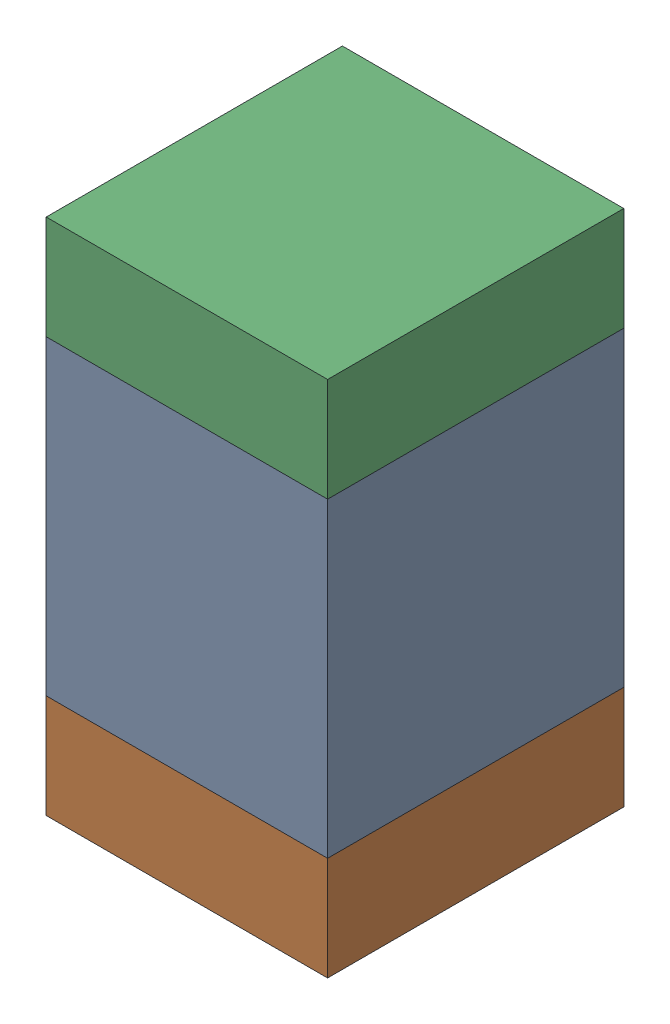
SolidWorks assembly C434PCB, configuration Default. Lengths in mm.
Overall size (0.95 1.75 1).
6 component instances, 2 part files, 0 mates.
Components (placement in the parent):
- 761616384-1: 761616384 [Default] at (113.2 95.4 -2.6638) size (0.95 1.05 1)
  - Extruded_5-1: Extruded_5 [Default] at origin size (0.95 1.05 1)
- 761616520-1: 761616520 [Default] at (113.2 94.7 -2.6638) size (0.95 0.35 1)
  - Extruded_6-1: Extruded_6 [Default] at origin size (0.95 0.35 1)
- 761616520-2: 761616520 [Default] at (113.2 96.1 -2.6638) size (0.95 0.35 1)
  - Extruded_6-1: Extruded_6 [Default] at origin size (0.95 0.35 1)
